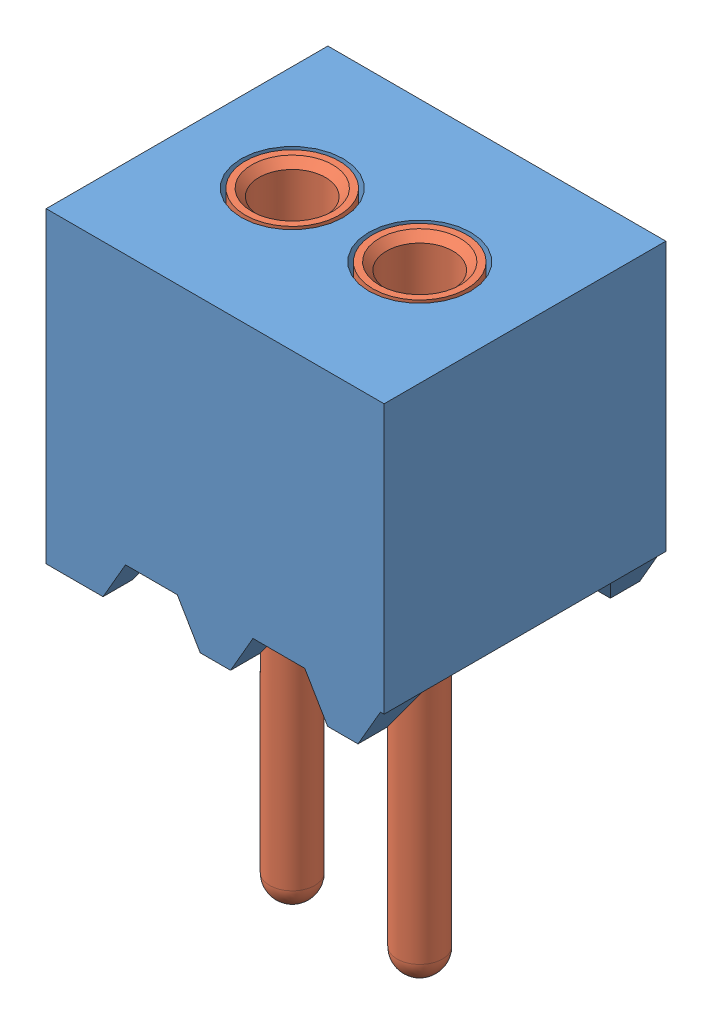
SolidWorks assembly mill-max-861-13-002-10-002000, configuration Default. Lengths in mm.
Overall size (2.65 4.83 2.21).
3 component instances, 2 part files, 0 mates.
Components (placement in the parent):
- mill-max-861-13-002-10-002000_P8XX-18-015-05-000000(P802-18-015-05-000000)-1: mill-max-861-13-002-10-002000_P8XX-18-015-05-000000(P802-18-015-05-000000) [Default] at origin size (2.65 2.41 2.21)
- mill-max-861-13-002-10-002000_0439-1: mill-max-861-13-002-10-002000_0439 [Default] at (1.8255 0 -1.1049) x (0 -1 0) z (0 0 1) size (4.83 0.74 0.74)
- mill-max-861-13-002-10-002000_0439-2: mill-max-861-13-002-10-002000_0439 [Default] at (0.8255 0 -1.1049) x (0 -1 0) z (0 0 1) size (4.83 0.74 0.74)
